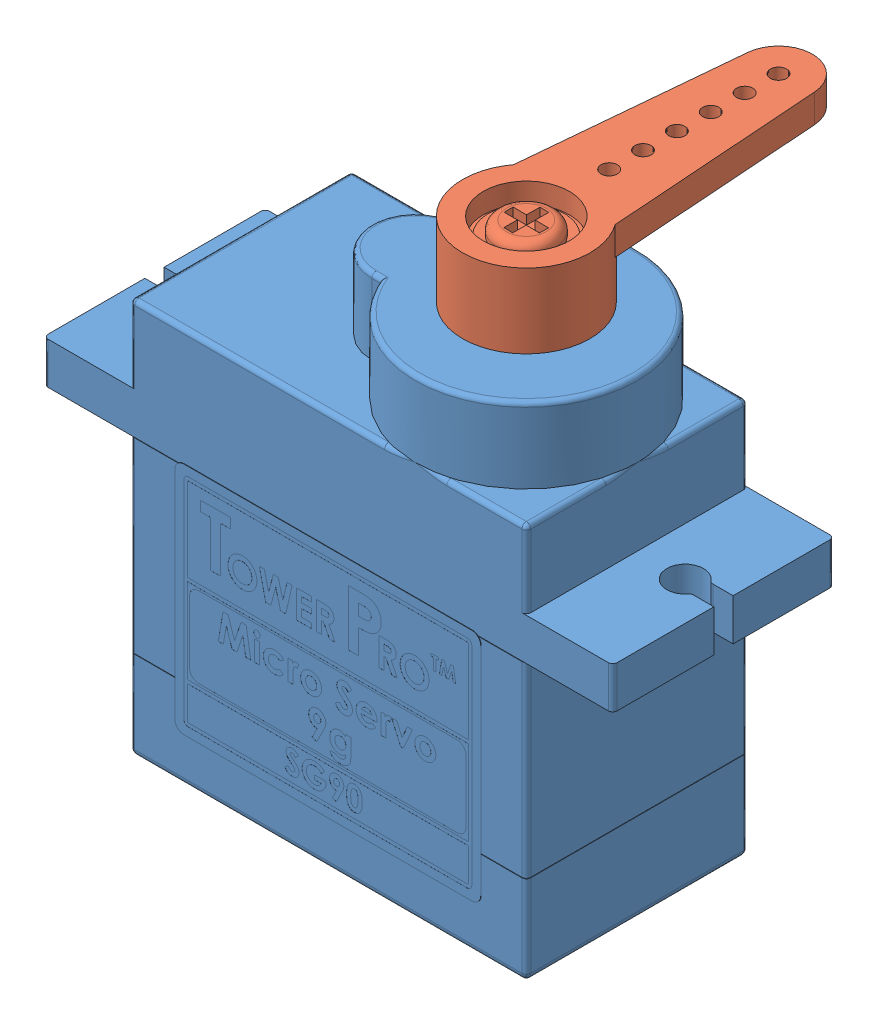
SolidWorks assembly SG90, configuration Default. Lengths in mm.
Overall size (32.36 31.5 22.48).
2 component instances, 2 part files, 2 mates.
Components (placement in the parent):
- SG90 BODY-1: SG90 BODY [Default] at (9.9674 8.0019 -5.2145) size (32.36 29.6 12.65)
- SG90 ARM-1: SG90 ARM [Default] at (3.6682 15.3806 1.0847) x (-0.011061 0 0.999939) z (-0.999939 0 -0.011061) size (19.74 4.23 7.24)
Mates (geometry in assembly coordinates):
- Concentric1: concentric aligned: cylinder of SG90 BODY-1 through (3.6682 51.1707 1.0847) axis (0 -1 0) radius 2.286; cylinder of SG90 ARM-1 through (3.6682 16.9935 1.0847) axis (0 -1 0) radius 3.6195
- Coincident1: coincident anti-aligned: plane of SG90 BODY-1 through (9.9674 15.1012 7.3839) normal (0 1 0); plane of SG90 ARM-1 through (3.6682 15.1012 1.0847) normal (0 -1 0)
